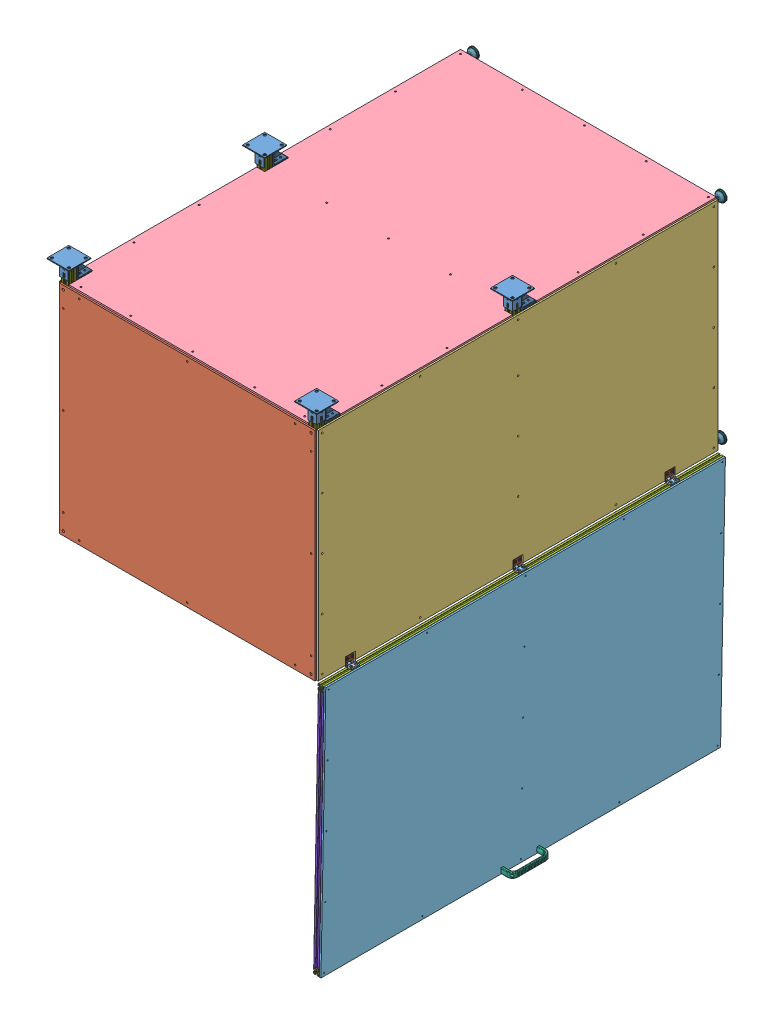
SolidWorks assembly Plant-imager Box v77, configuration Default. Lengths in mm.
Overall size (1396.07 2469.04 2084).
140 component instances, 35 part files, 0 mates.
Components (placement in the parent):
- Plant-imager Box v77.step-1: Plant-imager Box v77.step [Défaut] at origin size (1396.07 2469.04 2084)
  - HINGE 2.step-1: HINGE 2.step [Défaut] at (1266 -22.4999 1001) x (0.99982 -0.018996 0) z (0 0 -1) size (34 19.2 45.04)
    - HINGE.step-1: HINGE.step [Défaut] at origin size (34 19.2 45.04)
      - 1.step-1: 1.step [Défaut] at origin size (16.5 6 8)
      - 2.step-1: 2.step [Défaut] at origin size (12 12 12)
      - 3.step-1: 3.step [Défaut] at origin size (16.5 6 8)
      - 4.step-1: 4.step [Défaut] at origin size (12 12 12)
      - 6.step-1: 6.step [Défaut] at origin size (34 12 45.04)
  - HINGE 1.step-1: HINGE 1.step [Défaut] at (1266 -22.4999 1000) x (0 -1 0) z (0 0 -1) size (43 23.2 45.04)
    - HINGE_1.step-1: HINGE_1.step [Défaut] at origin size (43 23.2 45.04)
      - 5.step-1: 5.step [Défaut] at origin size (6 6 45)
      - 7.step-1: 7.step [Défaut] at origin size (19.6 8.7 10)
      - 8.step-1: 8.step [Défaut] at origin size (12 16 12)
      - 9.step-1: 9.step [Défaut] at origin size (19.6 8.7 10)
      - 10.step-1: 10.step [Défaut] at origin size (12 16 12)
      - 11.step-1: 11.step [Défaut] at origin size (43 12 45.04)
  - HINGE 1_1.step-1: HINGE 1_1.step [Défaut] at (1266 -22.4999 1838) x (0 -1 0) z (0 0 -1) size (43 23.2 45.04)
    - HINGE_2.step-1: HINGE_2.step [Défaut] at origin size (43 23.2 45.04)
      - 5.step-1: 5.step [Défaut] at origin size (6 6 45)
      - 7.step-1: 7.step [Défaut] at origin size (19.6 8.7 10)
      - 8.step-1: 8.step [Défaut] at origin size (12 16 12)
      - 9.step-1: 9.step [Défaut] at origin size (19.6 8.7 10)
      - 10.step-1: 10.step [Défaut] at origin size (12 16 12)
      - 11.step-1: 11.step [Défaut] at origin size (43 12 45.04)
  - HINGE 1_2.step-1: HINGE 1_2.step [Défaut] at (1266 -22.4999 238.5) x (0 -1 0) z (0 0 -1) size (43 23.2 45.04)
    - HINGE_3.step-1: HINGE_3.step [Défaut] at origin size (43 23.2 45.04)
      - 5.step-1: 5.step [Défaut] at origin size (6 6 45)
      - 7.step-1: 7.step [Défaut] at origin size (19.6 8.7 10)
      - 8.step-1: 8.step [Défaut] at origin size (12 16 12)
      - 9.step-1: 9.step [Défaut] at origin size (19.6 8.7 10)
      - 10.step-1: 10.step [Défaut] at origin size (12 16 12)
      - 11.step-1: 11.step [Défaut] at origin size (43 12 45.04)
  - HINGE 2_1.step-1: HINGE 2_1.step [Défaut] at (1266 -22.4999 1839) x (0.99982 -0.018996 0) z (0 0 -1) size (34 19.2 45.04)
    - HINGE_4.step-1: HINGE_4.step [Défaut] at origin size (34 19.2 45.04)
      - 1.step-1: 1.step [Défaut] at origin size (16.5 6 8)
      - 2.step-1: 2.step [Défaut] at origin size (12 12 12)
      - 3.step-1: 3.step [Défaut] at origin size (16.5 6 8)
      - 4.step-1: 4.step [Défaut] at origin size (12 12 12)
      - 6.step-1: 6.step [Défaut] at origin size (34 12 45.04)
  - HINGE 2_2.step-1: HINGE 2_2.step [Défaut] at (1266 -22.4999 239.5) x (0.99982 -0.018996 0) z (0 0 -1) size (34 19.2 45.04)
    - HINGE_5.step-1: HINGE_5.step [Défaut] at origin size (34 19.2 45.04)
      - 1.step-1: 1.step [Défaut] at origin size (16.5 6 8)
      - 2.step-1: 2.step [Défaut] at origin size (12 12 12)
      - 3.step-1: 3.step [Défaut] at origin size (16.5 6 8)
      - 4.step-1: 4.step [Défaut] at origin size (12 12 12)
      - 6.step-1: 6.step [Défaut] at origin size (34 12 45.04)
  - Profil 40x40 v2.step-1: Profil 40x40 v2.step [Défaut] at origin size (40 40 2000)
  - Profil 40x40 v2.step-2: Profil 40x40 v2.step [Défaut] at (1240 0 0) size (40 40 2000)
  - Profil 40x40 v1.step-1: Profil 40x40 v1.step [Défaut] at (20 0 20) x (0 0 -1) z (1 0 0) size (40 40 1200)
  - Profil 40x40 v1.step-2: Profil 40x40 v1.step [Défaut] at (20 0 1980) x (0 0 -1) z (1 0 0) size (40 40 1200)
  - Profil 40x40 v1.step-3: Profil 40x40 v1.step [Défaut] at (20 1046 20) x (0 0 -1) z (1 0 0) size (40 40 1200)
  - Profil 40x40 v1 (1).step-1: Profil 40x40 v1 (1).step [Défaut] at (0 20.0001 20.0001) x (1 0 0) z (0 1 0) size (40 40 1006)
  - Profil 40x40 v1 (1).step-2: Profil 40x40 v1 (1).step [Défaut] at (1240 20.0001 20.0001) x (1 0 0) z (0 1 0) size (40 40 1006)
  - Profil 40x40 v1 (2).step-1: Profil 40x40 v1 (2).step [Défaut] at (20 0 1600) x (0 0 -1) z (1 0 0) size (40 40 160)
  - Profil 40x40 v1 (2).step-2: Profil 40x40 v1 (2).step [Défaut] at (1060 0 1600) x (0 0 -1) z (1 0 0) size (40 40 160)
  - Profil 40x40 v1 (3).step-1: Profil 40x40 v1 (3).step [Défaut] at (0 1046 0) size (40 40 2000)
  - Profil 40x40 v1 (3).step-2: Profil 40x40 v1 (3).step [Défaut] at (1240 1046 0) size (40 40 2000)
  - Profil 40x40 v1 (4).step-1: Profil 40x40 v1 (4).step [Défaut] at (0 1026.0001 1979.9999) x (1 0 0) z (0 -1 0) size (40 40 1006)
  - Profil 40x40 v1 (4).step-2: Profil 40x40 v1 (4).step [Défaut] at (1240 1026.0001 1979.9999) x (1 0 0) z (0 -1 0) size (40 40 1006)
  - Planche 2 v4.step-1: Planche 2 v4.step [Défaut] at (-28 -19.9999 2008) x (0 0 -1) z (1 0 0) size (2000 1086 8)
  - STEEL_BASE.step-1: STEEL_BASE.step [Défaut] at (0 1170.0001 1980) x (0 0 1) z (0 -1 0) size (110 110 79)
  - STEEL_BASE.step-2: STEEL_BASE.step [Défaut] at (1240 1170.0001 1980) x (1 0 0) z (0 -1 0) size (110 110 79)
  - Planche 1.step-1: Planche 1.step [Défaut] at (-20 -19.9999 2000) size (1280 1086 8)
  - Planche 2.step-1: Planche 2.step [Défaut] at (1260 -19.9999 2008) x (0 0 -1) z (1 0 0) size (2000 1086 8)
  - Planche 3.step-1: Planche 3.step [Défaut] at (1268 1066.0001 2008) x (0 0 -1) z (0 1 0) size (2000 1280 8)
  - Planche 4.step-1: Planche 4.step [Défaut] at (1306.6537 -29.2734 2001) x (-0.018996 -0.99982 0) z (0 0 -1) size (1270 8 2000)
  - STRAP_SHAPED_HANDLE.step-1: STRAP_SHAPED_HANDLE.step [Défaut] at (1282.814 -1284.0469 1093) x (0 0 -1) z (-0.018996 -0.99982 0) size (194.99 58.02 26.01)
  - Profil 30x30 v1.step-1: Profil 30x30 v1.step [Défaut] at (1283.3729 -43.8338 2001) x (-0.018996 -0.99982 0) z (0 0 -1) size (30 30 2000)
  - Profil 30x30 v1.step-2: Profil 30x30 v1.step [Défaut] at (1259.8182 -1283.61 2001) x (-0.018996 -0.99982 0) z (0 0 -1) size (30 30 2000)
  - Profil 30x30 v1 (1).step-1: Profil 30x30 v1 (1).step [Défaut] at (1283.088 -58.831 1986) x (-0.99982 0.018996 0) z (-0.018996 -0.99982 0) size (30 30 1210)
  - Profil 30x30 v1 (1).step-2: Profil 30x30 v1 (1).step [Défaut] at (1283.088 -58.831 1001) x (-0.99982 0.018996 0) z (-0.018996 -0.99982 0) size (30 30 1210)
  - Profil 30x30 v1 (1).step-3: Profil 30x30 v1 (1).step [Défaut] at (1283.088 -58.831 16) x (-0.99982 0.018996 0) z (-0.018996 -0.99982 0) size (30 30 1210)
  - MAGNET_CATCH.step-1: MAGNET_CATCH.step [Défaut] at (20 -1.7501 1800) x (0 0 -1) z (1 0 0) size (48 29 21)
  - MAGNET_CATCH.step-2: MAGNET_CATCH.step [Défaut] at (20 -0.7501 250) x (0 0 -1) z (1 0 0) size (48 29 21)
  - brackets_ce-sb3680-8.step-1: brackets_ce-sb3680-8.step [Défaut] at (20 0.0001 1580) x (0 0 -1) z (0 -1 0) size (80 80 36)
  - brackets_ce-sb3680-8.step-2: brackets_ce-sb3680-8.step [Défaut] at (20 0.0001 1960) x (0 0 -1) z (0 -1 0) size (80 80 36)
  - brackets_ce-sb3680-8.step-3: brackets_ce-sb3680-8.step [Défaut] at (20 0.0001 40) x (1 0 0) z (0 -1 0) size (80 80 36)
  - brackets_ce-sb3680-8.step-4: brackets_ce-sb3680-8.step [Défaut] at (1220 0.0001 40) x (0 0 1) z (0 -1 0) size (80 80 36)
  - brackets_ce-sb3680-8.step-5: brackets_ce-sb3680-8.step [Défaut] at (1220 0.0001 1580) x (-1 0 0) z (0 -1 0) size (80 80 36)
  - brackets_ce-sb3680-8.step-6: brackets_ce-sb3680-8.step [Défaut] at (1220 0.0001 1960) x (-1 0 0) z (0 -1 0) size (80 80 36)
  - brackets_ce-sb3680-8.step-7: brackets_ce-sb3680-8.step [Défaut] at (0 20.0001 1960) x (0 1 0) z (-1 0 0) size (80 80 36)
  - brackets_ce-sb3680-8.step-8: brackets_ce-sb3680-8.step [Défaut] at (0 20.0001 980) x (0 1 0) z (-1 0 0) size (80 80 36)
  - brackets_ce-sb3680-8.step-9: brackets_ce-sb3680-8.step [Défaut] at (0 20.0001 40) x (0 0 1) z (-1 0 0) size (80 80 36)
  - brackets_ce-sb3680-8.step-10: brackets_ce-sb3680-8.step [Défaut] at (0 1026.0001 40) x (0 -1 0) z (-1 0 0) size (80 80 36)
  - brackets_ce-sb3680-8.step-11: brackets_ce-sb3680-8.step [Défaut] at (0 1026.0001 980) x (0 0 -1) z (-1 0 0) size (80 80 36)
  - brackets_ce-sb3680-8.step-12: brackets_ce-sb3680-8.step [Défaut] at (0 1026.0001 1960) x (0 0 -1) z (-1 0 0) size (80 80 36)
  - brackets_ce-sb3680-8.step-13: brackets_ce-sb3680-8.step [Défaut] at (1240 20.0001 1960) x (0 0 -1) z (1 0 0) size (80 80 36)
  - brackets_ce-sb3680-8.step-14: brackets_ce-sb3680-8.step [Défaut] at (1240 1026.0001 1960) x (0 -1 0) z (1 0 0) size (80 80 36)
  - brackets_ce-sb3680-8.step-15: brackets_ce-sb3680-8.step [Défaut] at (1240 20.0001 980) x (0 0 -1) z (1 0 0) size (80 80 36)
  - brackets_ce-sb3680-8.step-16: brackets_ce-sb3680-8.step [Défaut] at (1240 1026.0001 980) x (0 -1 0) z (1 0 0) size (80 80 36)
  - brackets_ce-sb3680-8.step-17: brackets_ce-sb3680-8.step [Défaut] at (1240 20.0001 40) x (0 1 0) z (1 0 0) size (80 80 36)
  - brackets_ce-sb3680-8.step-18: brackets_ce-sb3680-8.step [Défaut] at (1240 1026.0001 40) x (0 0 1) z (1 0 0) size (80 80 36)
  - brackets_ce-sb3680-8.step-19: brackets_ce-sb3680-8.step [Défaut] at (1220 1046.0001 1960) x (0 0 -1) z (0 1 0) size (80 80 36)
  - brackets_ce-sb3680-8.step-20: brackets_ce-sb3680-8.step [Défaut] at (20 1046.0001 1960) x (1 0 0) z (0 1 0) size (80 80 36)
  - brackets_ce-sb3680-8.step-21: brackets_ce-sb3680-8.step [Défaut] at (1220 1046.0001 980) x (0 0 -1) z (0 1 0) size (80 80 36)
  - brackets_ce-sb3680-8.step-22: brackets_ce-sb3680-8.step [Défaut] at (20 1046.0001 980) x (1 0 0) z (0 1 0) size (80 80 36)
  - brackets_ce-sb3680-8.step-23: brackets_ce-sb3680-8.step [Défaut] at (1220 1046.0001 40) x (-1 0 0) z (0 1 0) size (80 80 36)
  - brackets_ce-sb3680-8.step-24: brackets_ce-sb3680-8.step [Défaut] at (20 1046.0001 40) x (0 0 1) z (0 1 0) size (80 80 36)
  - brackets_ce-sb3680-8.step-25: brackets_ce-sb3680-8.step [Défaut] at (1220 1046.0001 1600) x (0 0 -1) z (0 1 0) size (80 80 36)
  - brackets_ce-sb3680-8.step-26: brackets_ce-sb3680-8.step [Défaut] at (20 1046.0001 1600) x (1 0 0) z (0 1 0) size (80 80 36)
  - Profil 40x40 v1 (2).step-3: Profil 40x40 v1 (2).step [Défaut] at (20 1046 1620) x (0 0 -1) z (1 0 0) size (40 40 160)
  - Profil 40x40 v1 (2).step-4: Profil 40x40 v1 (2).step [Défaut] at (1060 1046 1620) x (0 0 -1) z (1 0 0) size (40 40 160)
  - Magnet.step-1: Magnet.step [Défaut] at (1240.0243 -1260.7299 1776.5) x (0 0 -1) z (0.018996 0.99982 0) size (41 2 14)
  - Magnet bracket.step-1: Magnet bracket.step [Défaut] at (1242.8812 -1268.2855 1781.5) x (0 0 -1) z (0.018996 0.99982 0) size (69 30 21)
  - Magnet bracket.step-2: Magnet bracket.step [Défaut] at (1242.8812 -1268.2855 231.5) x (0 0 -1) z (0.018996 0.99982 0) size (69 30 21)
  - Magnet.step-2: Magnet.step [Défaut] at (1240.0053 -1261.7297 226.5) x (0 0 -1) z (0.018996 0.99982 0) size (41 2 14)
  - BRACKET_30X60.step-1: BRACKET_30X60.step [Défaut] at (1283.088 -58.831 31) x (-0.99982 0.018996 0) z (-0.018996 -0.99982 0) size (28 57 57)
  - BRACKET_30X60.step-2: BRACKET_30X60.step [Défaut] at (1260.1031 -1268.6127 31) x (-0.99982 0.018996 0) z (0 0 1) size (28 57 57)
  - BRACKET_30X60.step-3: BRACKET_30X60.step [Défaut] at (1283.088 -58.831 1016) x (-0.99982 0.018996 0) z (-0.018996 -0.99982 0) size (28 57 57)
  - BRACKET_30X60.step-4: BRACKET_30X60.step [Défaut] at (1260.1031 -1268.6127 1016) x (-0.99982 0.018996 0) z (0 0 1) size (28 57 57)
  - BRACKET_30X60.step-5: BRACKET_30X60.step [Défaut] at (1283.088 -58.831 986) x (-0.99982 0.018996 0) z (0 0 -1) size (28 57 57)
  - BRACKET_30X60.step-6: BRACKET_30X60.step [Défaut] at (1260.1031 -1268.6127 986) x (-0.99982 0.018996 0) z (0.018996 0.99982 0) size (28 57 57)
  - BRACKET_30X60.step-7: BRACKET_30X60.step [Défaut] at (1283.088 -58.831 1971) x (-0.99982 0.018996 0) z (0 0 -1) size (28 57 57)
  - BRACKET_30X60.step-8: BRACKET_30X60.step [Défaut] at (1260.1031 -1268.6127 1971) x (-0.99982 0.018996 0) z (0.018996 0.99982 0) size (28 57 57)
  - HINGED_FOOT.step-1: HINGED_FOOT.step [Défaut] at (0 0.0001 -44) size (44 44 85)
  - DAMPING_RING_D44.step-1: DAMPING_RING_D44.step [Défaut] at (0 0.0001 -48) size (52 52 10)
  - Profil 40x40 v1 (5).step-1: Profil 40x40 v1 (5).step [Défaut] at (0 1166.0001 1979.9999) x (1 0 0) z (0 -1 0) size (40 40 100)
  - STEEL_BASE.step-3: STEEL_BASE.step [Défaut] at (0 1170.0001 1000) x (0 0 1) z (0 -1 0) size (110 110 79)
  - STEEL_BASE.step-4: STEEL_BASE.step [Défaut] at (1240 1170.0001 1000) x (1 0 0) z (0 -1 0) size (110 110 79)
  - Profil 40x40 v1 (5).step-2: Profil 40x40 v1 (5).step [Défaut] at (1240 1166.0001 1979.9999) x (1 0 0) z (0 -1 0) size (40 40 100)
  - Profil 40x40 v1 (5).step-3: Profil 40x40 v1 (5).step [Défaut] at (1240 1166.0001 999.9999) x (1 0 0) z (0 -1 0) size (40 40 100)
  - Profil 40x40 v1 (5).step-4: Profil 40x40 v1 (5).step [Défaut] at (0 1166.0001 999.9999) x (1 0 0) z (0 -1 0) size (40 40 100)
  - DAMPING_RING_D44.step-2: DAMPING_RING_D44.step [Défaut] at (1240 0.0001 -48) size (52 52 10)
  - HINGED_FOOT.step-2: HINGED_FOOT.step [Défaut] at (1240 0.0001 -44) size (44 44 85)
  - HINGED_FOOT.step-3: HINGED_FOOT.step [Défaut] at (1240 1046.0001 -45) size (44 44 85)
  - DAMPING_RING_D44.step-3: DAMPING_RING_D44.step [Défaut] at (1240 1046.0001 -49) size (52 52 10)
  - HINGED_FOOT.step-4: HINGED_FOOT.step [Défaut] at (0 1046.0001 -45) size (44 44 85)
  - DAMPING_RING_D44.step-4: DAMPING_RING_D44.step [Défaut] at (0 1046.0001 -49) size (52 52 10)
  - Profil 40x40 v1 (1).step-3: Profil 40x40 v1 (1).step [Défaut] at (0 20.0001 1000.0001) x (1 0 0) z (0 1 0) size (40 40 1006)
  - Profil 40x40 v1 (1).step-4: Profil 40x40 v1 (1).step [Défaut] at (1240 20.0001 1000.0001) x (1 0 0) z (0 1 0) size (40 40 1006)
  - Profil 40x40 v1.step-4: Profil 40x40 v1.step [Défaut] at (20 1046 1000) x (0 0 -1) z (1 0 0) size (40 40 1200)
  - Profil 40x40 v1.step-5: Profil 40x40 v1.step [Défaut] at (20 1046 1980) x (0 0 -1) z (1 0 0) size (40 40 1200)
  - brackets_ce-sb3680-8.step-27: brackets_ce-sb3680-8.step [Défaut] at (1240 1066.0001 980) x (0 0 -1) z (1 0 0) size (80 80 36)
  - brackets_ce-sb3680-8.step-28: brackets_ce-sb3680-8.step [Défaut] at (1240 1066.0001 1960) x (0 0 -1) z (1 0 0) size (80 80 36)
  - brackets_ce-sb3680-8.step-29: brackets_ce-sb3680-8.step [Défaut] at (0 1066.0001 1960) x (0 0 -1) z (1 0 0) size (80 80 36)
  - brackets_ce-sb3680-8.step-30: brackets_ce-sb3680-8.step [Défaut] at (0 1066.0001 980) x (0 0 -1) z (1 0 0) size (80 80 36)
  - LED Strip U channel.step-1: LED Strip U channel.step [Défaut] at (-20 514.1751 1050) x (0 1 0) z (1 0 0) size (17.65 900 7.87)
  - LED Strip U channel.step-2: LED Strip U channel.step [Défaut] at (611.175 1066.0001 1050) x (1 0 0) z (0 -1 0) size (17.65 900 7.87)
  - LED Strip U channel.step-3: LED Strip U channel.step [Défaut] at (1260 550.3251 1050) x (0 -1 0) z (-1 0 0) size (17.65 900 7.87)
  - LED Strip U channel.step-4: LED Strip U channel.step [Défaut] at (1286.7605 -655.1834 1051) x (-0.018996 -0.99982 0) z (-0.99982 0.018996 0) size (17.65 900 7.87)
